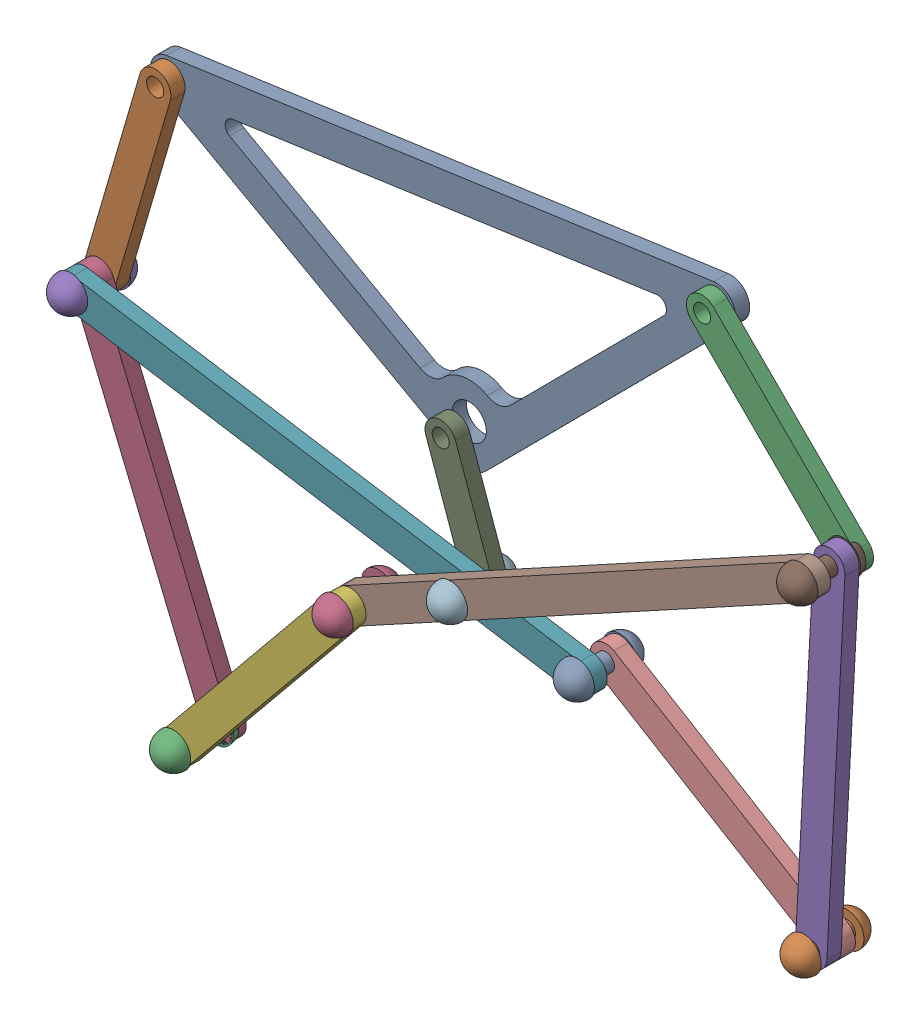
SolidWorks assembly strider_assembly, configuration Default. Lengths in mm.
Overall size (277.42 220.76 39.47).
17 component instances, 7 part files, 36 mates.
Components (placement in the parent):
- link_1-1: link_1 [Default] at (-52.7587 76.5546 43.467) x (0.99005 0.140717 0.000188) z (-0.00022 0.000212 1) size (207.21 86.7 5)
- link_3_and_8-1: link_3_and_8 [Default] at (-157.5765 22.694 48.4554) x (0.280402 0.959883 -0.000142) z (-0.00022 0.000212 1) size (81 11 5)
- link_3_and_8-2: link_3_and_8 [Default] at (68.9431 58.882 48.4975) x (-0.709026 0.705182 -0.000306) z (-0.00022 0.000212 1) size (81 11 5)
- link_4_and_7-1: link_4_and_7 [Default] at (-144.3222 -66.2885 53.4772) x (-0.384492 0.923128 -0.000281) z (-0.00022 0.000212 1) size (131 11 5)
- link_4_and_7-2: link_4_and_7 [Default] at (90.6024 -25.7153 53.5202) x (0.052592 0.998616 -0.000201) z (-0.00022 0.000212 1) size (131 11 5)
- link_5_and_6-1: link_5_and_6 [Default] at (-92.7481 -86.8549 68.4929) x (0.633508 0.773736 -0.000025) z (-0.00022 0.000212 1) size (101 11 5)
- link_10_and_9-1: link_10_and_9 [Default] at (-78.5083 -25.0261 58.4829) x (0.987605 -0.156959 0.00025) z (-0.00022 0.000212 1) size (191 11 5)
- link_10_and_9-2: link_10_and_9 [Default] at (14.7583 -8.917 63.4999) x (-0.877749 -0.47912 -0.000091) z (-0.00022 0.000212 1) size (191 11 5)
- crank_lin_2-1: crank_lin_2 [Default] at (-35.8446 -14.0371 53.4899) x (-0.335881 0.941905 -0.000274) z (-0.00022 0.000212 1) size (51 11 5)
- link_5_and_6-3: link_5_and_6 [Default] at (48.9131 -62.3939 48.5188) x (0.856329 -0.51643 0.000298) z (-0.00022 0.000212 1) size (101 11 5)
- stud-12: stud [Default] at (93.7568 34.2027 58.5082) x (1 0 0.00022) z (-0.00022 0.000212 1) size (12 12 27)
- stud-16: stud [Default] at (-29.1281 -32.8741 58.4954) x (1 0 0.00022) z (-0.00022 0.000212 1) size (12 12 27)
- stud-17: stud [Default] at (10.3772 -39.1535 53.5054) x (0.999213 0.039655 0.000211) z (-0.00022 0.000212 1) size (12 12 27)
- stud-25: stud [Default] at (87.4474 -85.6328 51.0322) x (0.832886 -0.553445 0.000301) z (-0.00022 0.000212 1) size (12 12 27)
- stud-26: stud [Default] at (-121.2549 -121.6741 63.494) x (0.999922 0.012484 0.000217) z (-0.00022 0.000212 1) size (12 12 27)
- stud-28: stud [Default] at (-64.2392 -52.0378 63.4917) x (0.703243 0.710949 0.000004) z (-0.00022 0.000212 1) size (12 12 27)
- stud-29: stud [Default] at (-167.3917 -10.9008 53.4603) x (-0.703439 -0.710756 -0.000004) z (-0.00022 0.000212 1) size (12 12 27)
Mates (geometry in assembly coordinates):
- Concentric2: concentric aligned: cylinder of link_1-1 through (-147.7619 56.2893 45.9504) axis (0.00022 -0.000212 -1) radius 3; cylinder of link_3_and_8-1 through (-147.763 56.2904 50.9504) axis (0.00022 -0.000212 -1) radius 3
- Coincident2: coincident anti-aligned: plane of link_1-1 through (-41.5019 -2.6489 45.9863) normal (-0.00022 0.000212 1); plane of link_3_and_8-1 through (-147.7619 56.2893 45.9504) normal (0.00022 -0.000212 -1)
- Concentric4: concentric aligned: cylinder of link_1-1 through (44.1277 83.5628 45.9868) axis (0.00022 -0.000212 -1) radius 3; cylinder of link_3_and_8-2 through (44.1266 83.5639 50.9868) axis (0.00022 -0.000212 -1) radius 3
- Coincident3: coincident anti-aligned: plane of link_1-1 through (-41.5019 -2.6489 45.9863) normal (-0.00022 0.000212 1); plane of link_3_and_8-2 through (44.1277 83.5628 45.9868) normal (0.00022 -0.000212 -1)
- Concentric6: concentric aligned: cylinder of link_3_and_8-1 through (-167.3912 -10.9014 50.9603) axis (0.00022 -0.000212 -1) radius 3; cylinder of link_4_and_7-1 through (-167.3923 -10.9003 55.9603) axis (0.00022 -0.000212 -1) radius 3
- Coincident4: coincident anti-aligned: plane of link_3_and_8-1 through (-147.763 56.2904 50.9504) normal (-0.00022 0.000212 1); plane of link_4_and_7-1 through (-121.2521 -121.6768 50.994) normal (0.00022 -0.000212 -1)
- Concentric8: concentric aligned: cylinder of link_3_and_8-2 through (93.7584 34.2012 51.0082) axis (0.00022 -0.000212 -1) radius 3; cylinder of link_4_and_7-2 through (93.7573 34.2022 56.0082) axis (0.00022 -0.000212 -1) radius 3
- Coincident5: coincident anti-aligned: plane of link_3_and_8-2 through (44.1266 83.5639 50.9868) normal (-0.00022 0.000212 1); plane of link_4_and_7-2 through (87.4474 -85.6328 51.0322) normal (0.00022 -0.000212 -1)
- Concentric10: concentric aligned: cylinder of link_4_and_7-1 through (-121.2532 -121.6757 55.994) axis (0.00022 -0.000212 -1) radius 3; cylinder of link_5_and_6-1 through (-121.2565 -121.6725 70.994) axis (0.00022 -0.000212 -1) radius 3
- Coincident7: coincident anti-aligned: plane of link_4_and_7-1 through (-121.2532 -121.6757 55.994) normal (-0.00022 0.000212 1); plane of link_10_and_9-1 through (-167.3923 -10.9003 55.9603) normal (0.00022 -0.000212 -1)
- Concentric17: concentric aligned: cylinder of link_5_and_6-1 through (-64.2408 -52.0362 70.9917) axis (0.00022 -0.000212 -1) radius 3; cylinder of link_10_and_9-2 through (-64.2397 -52.0373 65.9917) axis (0.00022 -0.000212 -1) radius 3
- Concentric18: concentric aligned: cylinder of link_10_and_9-1 through (-29.1286 -32.8736 60.9954) axis (0.00022 -0.000212 -1) radius 3; cylinder of link_10_and_9-2 through (-29.1297 -32.8725 65.9954) axis (0.00022 -0.000212 -1) radius 3
- Concentric24: concentric aligned: cylinder of link_4_and_7-1 through (-167.3923 -10.9003 55.9603) axis (0.00022 -0.000212 -1) radius 3; cylinder of link_10_and_9-1 through (-167.3933 -10.8993 60.9603) axis (0.00022 -0.000212 -1) radius 3
- Concentric25: concentric aligned: cylinder of link_10_and_9-2 through (-29.1297 -32.8725 65.9954) axis (0.00022 -0.000212 -1) radius 3; cylinder of crank_lin_2-1 through (-29.1275 -32.8746 55.9954) axis (0.00022 -0.000212 -1) radius 3
- Coincident15: coincident anti-aligned: plane of link_10_and_9-1 through (-167.3923 -10.9003 55.9603) normal (0.00022 -0.000212 -1); plane of crank_lin_2-1 through (-29.1275 -32.8746 55.9954) normal (-0.00022 0.000212 1)
- Concentric26: concentric aligned: cylinder of crank_lin_2-1 through (-42.5628 4.8016 55.9844) axis (0.00022 -0.000212 -1) radius 3; cylinder of link_1-1 through (-42.5606 4.7994 45.9844) axis (0.00022 -0.000212 -1) radius 6
- Concentric27: concentric aligned: cylinder of link_4_and_7-2 through (93.7573 34.2022 56.0082) axis (0.00022 -0.000212 -1) radius 3; cylinder of link_10_and_9-2 through (93.7552 34.2043 66.0082) axis (0.00022 -0.000212 -1) radius 3
- Concentric29: concentric aligned: cylinder of link_4_and_7-2 through (87.4463 -85.6317 56.0322) axis (0.00022 -0.000212 -1) radius 3; cylinder of link_5_and_6-3 through (87.4474 -85.6328 51.0322) axis (0.00022 -0.000212 -1) radius 3
- Coincident19: coincident anti-aligned: plane of link_4_and_7-2 through (87.4474 -85.6328 51.0322) normal (0.00022 -0.000212 -1); plane of link_5_and_6-3 through (10.3778 -39.1541 51.0054) normal (-0.00022 0.000212 1)
- Concentric30: concentric aligned: cylinder of link_10_and_9-1 through (10.3756 -39.1519 61.0054) axis (0.00022 -0.000212 -1) radius 3; cylinder of link_5_and_6-3 through (10.3778 -39.1541 51.0054) axis (0.00022 -0.000212 -1) radius 3
- Concentric31: concentric aligned: cylinder of link_10_and_9-1 through (10.3756 -39.1519 61.0054) axis (0.00022 -0.000212 -1) radius 3; cylinder of stud-17 through (10.3811 -39.1573 35.6554) axis (0.00022 -0.000212 -1) radius 3
- Coincident20: coincident anti-aligned: plane of link_10_and_9-1 through (-167.3933 -10.8993 60.9603) normal (-0.00022 0.000212 1); plane of stud-17 through (10.2566 -36.1543 61.0047) normal (0.00022 -0.000212 -1)
- Concentric32: concentric aligned: cylinder of link_10_and_9-2 through (-29.1297 -32.8725 65.9954) axis (0.00022 -0.000212 -1) radius 3; cylinder of stud-16 through (-29.1242 -32.8779 40.6454) axis (0.00022 -0.000212 -1) radius 3
- Coincident21: coincident anti-aligned: plane of link_10_and_9-2 through (93.7552 34.2043 66.0082) normal (-0.00022 0.000212 1); plane of stud-16 through (-29.1297 -29.8725 65.9948) normal (0.00022 -0.000212 -1)
- Concentric37: concentric aligned: cylinder of link_4_and_7-2 through (87.4463 -85.6317 56.0322) axis (0.00022 -0.000212 -1) radius 3; cylinder of stud-25 through (87.4513 -85.6366 33.1822) axis (0.00022 -0.000212 -1) radius 3
- Width8: width anti-aligned: plane of stud-25 through (89.1061 -83.1325 58.5321) normal (0.00022 -0.000212 -1); plane of link_5_and_6-3 through (89.1094 -83.1357 43.5321) normal (-0.00022 0.000212 1); plane of stud-25 through (10.3789 -39.1551 46.0054) normal (0.00022 -0.000212 -1); plane of link_4_and_7-2 through (87.4463 -85.6317 56.0322) normal (-0.00022 0.000212 1)
- Concentric39: concentric aligned: cylinder of link_10_and_9-2 through (93.7552 34.2043 66.0082) axis (0.00022 -0.000212 -1) radius 3; cylinder of stud-12 through (93.7607 34.199 40.6582) axis (0.00022 -0.000212 -1) radius 3
- Coincident23: coincident anti-aligned: plane of link_10_and_9-2 through (93.7552 34.2043 66.0082) normal (-0.00022 0.000212 1); plane of stud-12 through (93.7552 37.2043 66.0075) normal (0.00022 -0.000212 -1)
- Coincident24: coincident anti-aligned: plane of link_10_and_9-1 through (-167.3933 -10.8993 60.9603) normal (-0.00022 0.000212 1); plane of link_10_and_9-2 through (93.7562 34.2033 61.0082) normal (0.00022 -0.000212 -1)
- Coincident25: coincident anti-aligned: plane of link_5_and_6-1 through (-121.2554 -121.6736 65.994) normal (0.00022 -0.000212 -1); plane of link_10_and_9-2 through (93.7552 34.2043 66.0082) normal (-0.00022 0.000212 1)
- Concentric40: concentric aligned: cylinder of link_5_and_6-1 through (-121.2565 -121.6725 70.994) axis (0.00022 -0.000212 -1) radius 3; cylinder of stud-26 through (-121.2509 -121.6779 45.644) axis (0.00022 -0.000212 -1) radius 3
- Coincident26: coincident anti-aligned: plane of link_5_and_6-1 through (-121.2565 -121.6725 70.994) normal (-0.00022 0.000212 1); plane of stud-26 through (-121.294 -118.6728 70.9934) normal (0.00022 -0.000212 -1)
- Concentric41: concentric aligned: cylinder of link_5_and_6-1 through (-64.2408 -52.0362 70.9917) axis (0.00022 -0.000212 -1) radius 3; cylinder of stud-28 through (-64.2352 -52.0416 45.6417) axis (0.00022 -0.000212 -1) radius 3
- Coincident27: coincident anti-aligned: plane of link_5_and_6-1 through (-121.2565 -121.6725 70.994) normal (-0.00022 0.000212 1); plane of stud-28 through (-66.3737 -49.9265 70.9908) normal (0.00022 -0.000212 -1)
- Concentric42: concentric aligned: cylinder of link_10_and_9-1 through (-167.3933 -10.8993 60.9603) axis (0.00022 -0.000212 -1) radius 3; cylinder of stud-29 through (-167.3878 -10.9046 35.6103) axis (0.00022 -0.000212 -1) radius 3
- Coincident28: coincident anti-aligned: plane of link_10_and_9-1 through (-167.3933 -10.8993 60.9603) normal (-0.00022 0.000212 1); plane of stud-29 through (-165.2611 -13.0096 60.9613) normal (0.00022 -0.000212 -1)
